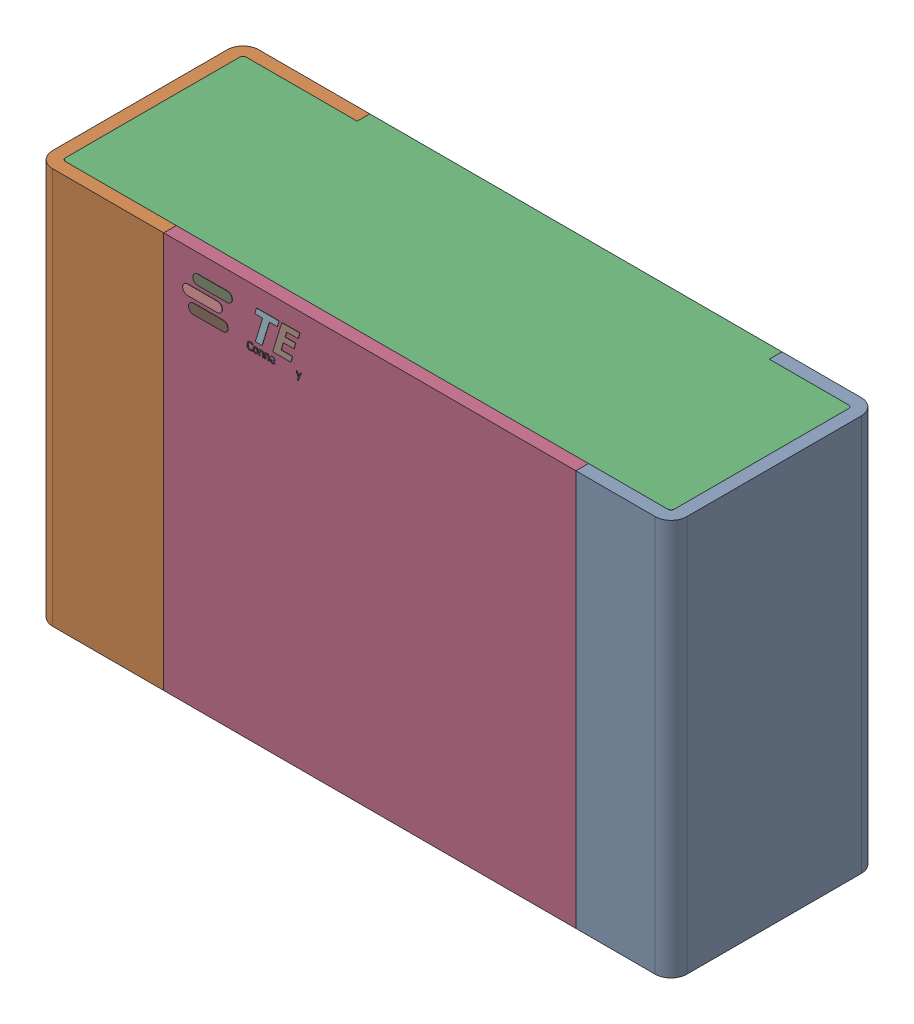
SolidWorks assembly R2.step, configuration Default. Lengths in mm.
Overall size (2 1.25 0.65).
5 component instances, 4 part files, 0 mates.
Components (placement in the parent):
- Res_TE_Connectivity_CPF0805B66R5E1_eec.step-1: Res_TE_Connectivity_CPF0805B66R5E1_eec.step [Default] at (42.037 32.512 0) size (2 1.25 0.65)
  - 1.step-1: 1.step [Default] at origin size (2 1.25 0.65)
  - 2.step-1: 2.step [Default] at origin size (1.92 1.25 0.61)
  - 3.step-1: 3.step [Default] at origin size (1.3 1.25 0.04)
  - TE connectivity Logo 1 (2).step-1: TE connectivity Logo 1 (2).step [Default] at (5.4285 0.313 0.551) x (-1 0 0) z (0 0 1) size (0.37 0.13 0.11)
